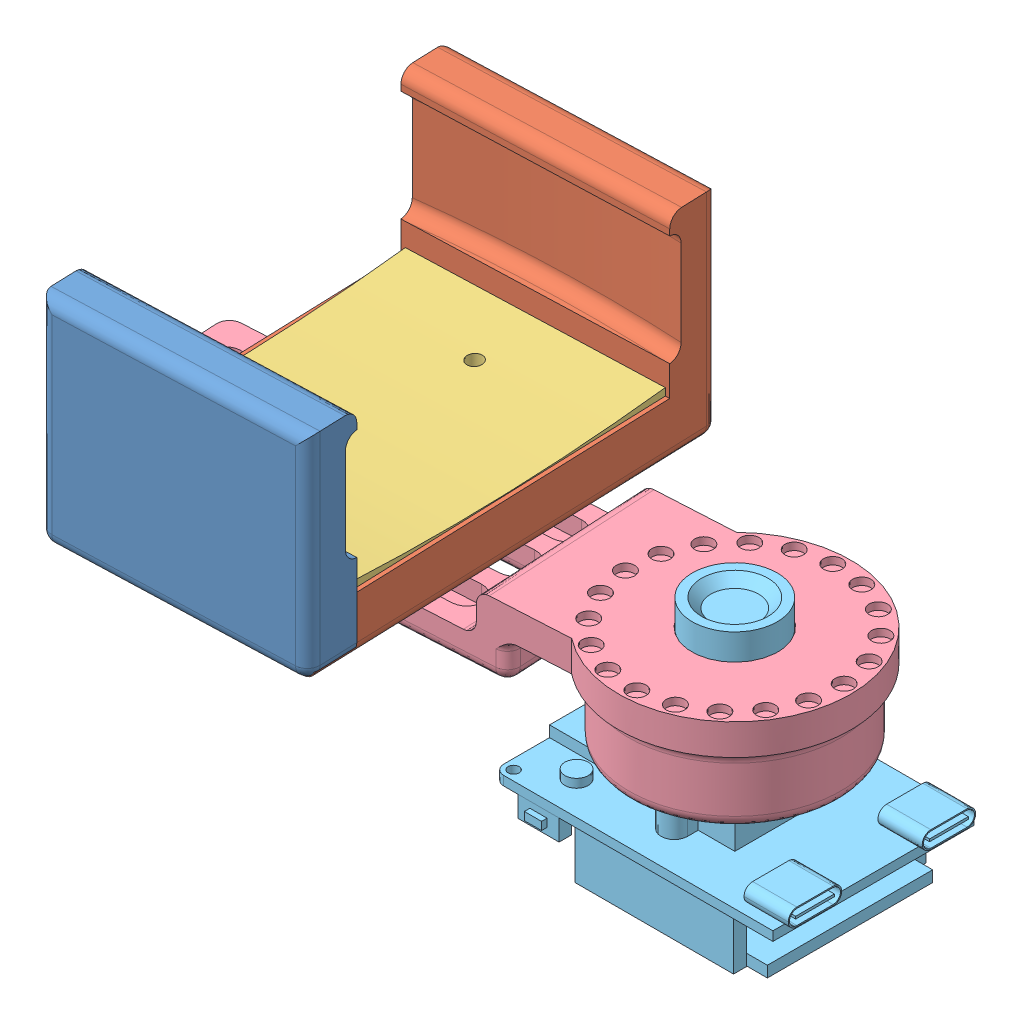
SolidWorks assembly E_soporte_V4, configuration Predeterminado. Lengths in mm.
Overall size (115.71 61.9 70.64).
5 component instances, 5 part files, 11 mates.
Components (placement in the parent):
- Soporte_prueba_V4b-1: Soporte_prueba_V4b [Predeterminado] at (-94.0573 0.9011 89.7318) x (-0.999391 0 0.034899) z (-0.034899 0 -0.999391) size (42.34 34.87 60.9)
- Soporte_prueba_V4d-1: Soporte_prueba_V4d [Predeterminado] at (-75.7013 12.2285 85.8091) x (0.999391 0 -0.034899) z (0.034899 0 0.999391) size (42.3 35 67.9)
- Soporte_prueba_V4c-1: Soporte_prueba_V4c [Predeterminado] at (-85.569 8.7011 83.1907) x (0.034899 0 0.999391) z (-0.999391 0 0.034899) size (52.8 2.5 40.9)
- Soporte_prueba_V4a-1: Soporte_prueba_V4a [Predeterminado] at (-95.3057 3.0525 77.4364) x (-0.054989 0 -0.998487) z (-0.998487 0 0.054989) size (37.8 16.5 109.9)
- MAIXII-1: MAIXII [Predeterminado] at (-47.8003 -17.4989 85.6128) size (47.8 37.7 34.3)
Mates (geometry in assembly coordinates):
- Coincidente6: coincident anti-aligned: plane of Pieza2-1 through (-78.109 5.9011 117.1505) normal (-0.034899 0 -0.999391); plane of Pieza4-1 through (-74.6111 12.2285 117.0284) normal (0.034899 0 0.999391)
- Coincidente7: coincident anti-aligned: plane of Pieza2-1 through (-94.0573 2.2011 89.7318) normal (0 -1 0); plane of Pieza4-1 through (-75.7013 2.2011 85.8091) normal (0 1 0)
- Coincidente8: coincident aligned: plane of Pieza2-1 through (-74.6111 35.9011 117.0284) normal (0.999391 0 -0.034899); plane of Pieza4-1 through (-75.7013 12.2285 85.8091) normal (0.999391 0 -0.034899)
- Coincidente9: coincident anti-aligned: plane of Pieza4-1 through (-118.0285 8.7011 65.7124) normal (0.999391 0 -0.034899); plane of Pieza3-1 through (-118.0285 11.2011 65.7124) normal (-0.999391 0 0.034899)
- Coincidente10: coincident anti-aligned: plane of Pieza4-1 through (-118.728 10.0011 65.7368) normal (0.034899 0 0.999391); plane of Pieza3-1 through (-77.1534 11.2011 64.285) normal (-0.034899 0 -0.999391)
- Coincidente11: coincident anti-aligned: plane of Pieza4-1 through (-75.7013 8.7011 85.8091) normal (0 1 0); plane of Pieza3-1 through (-85.569 8.7011 83.1907) normal (0 -1 0)
- Coincidente12: coincident anti-aligned: plane of Soporte_prueba_V4d-1 through (-116.6445 0.9011 125.4004) normal (0 -1 0); plane of 1-1 through (-67.819 0.9011 104.3657) normal (0 1 0)
- Ranura1: slot aligned: cylinder of Soporte_prueba_V4d-1 through (-96.6574 28.783 91.7324) axis (0 -1 0) radius 4.35; plane of Soporte_prueba_V4a-1 through (-75.2078 24.3011 87.4965) normal (0.054989 0 0.998487); cylinder of Soporte_prueba_V4a-1 through (-118.2746 24.3011 92.9229) axis (0 -1 0) radius 3.05
- Coincidente13: coincident anti-aligned: plane of 1-1 through (-41.4361 -8.9989 88.6912) normal (0 -1 0); plane of MAIXII-1 through (-47.8003 -8.9989 85.6128) normal (0 1 0)
- Paralelo1: parallel aligned: plane of 1-1 through (-52.8417 7.5011 103.5408) normal (0 1 0); plane of MAIXII-1 through (-41.4361 11.7011 88.6912) normal (0 1 0)
- Concéntrica1: concentric aligned: cylinder of 1-1 through (-41.4361 11.5011 88.6912) axis (0 -1 0) radius 7; cylinder of MAIXII-1 through (-41.4361 2.1011 88.6912) axis (0 -1 0) radius 7.25
